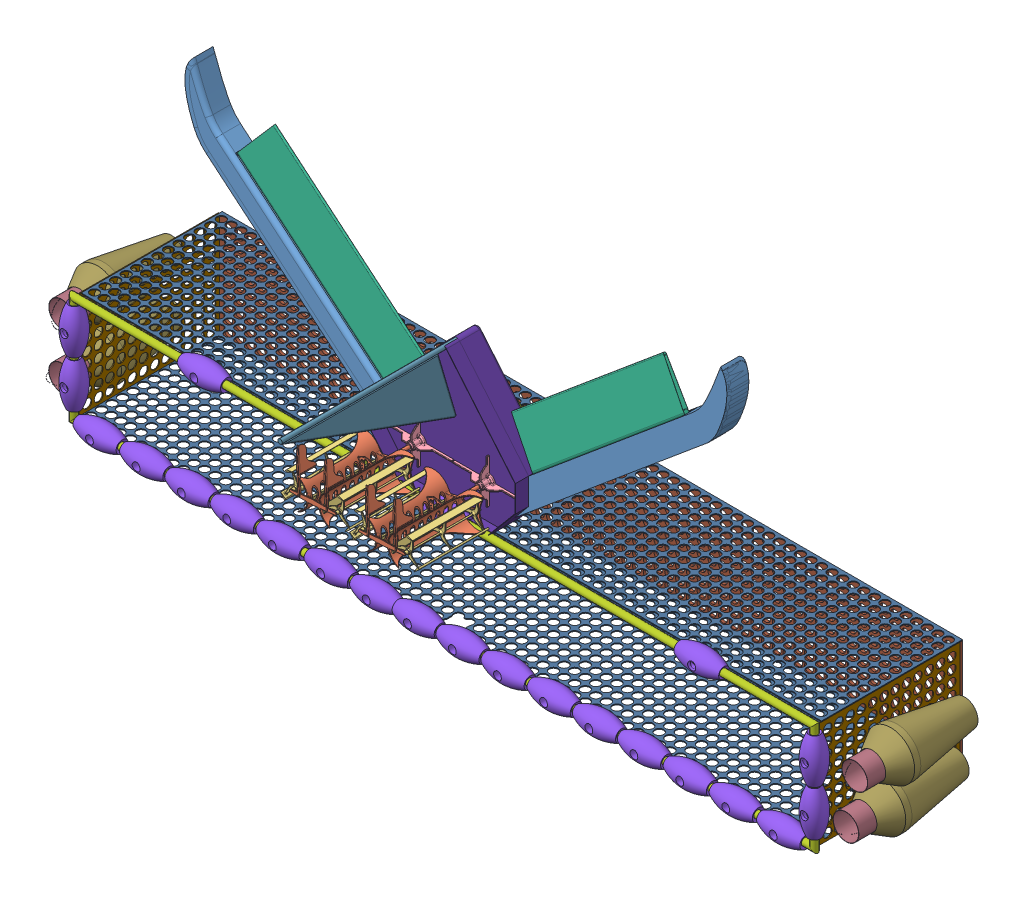
SolidWorks assembly Assembly, configuration Default. Lengths in mm.
Overall size (190923.81 84121.5 70808.31).
66 component instances, 17 part files, 22 mates.
Components (placement in the parent):
- base wings-1: base wings [Default] at (31251.053 -1037.9703 62574.9712) x (0.999998 -0.001756 0) z (0 0 1) size (49778.52 53495.45 5546.51)
- base wings-2: base wings [Default] at (4651.316 -721.6825 67574.9712) x (-1 0 0) z (0 0 -1) size (49778.52 53495.45 5546.51)
- windmill-1: windmill [Default] at (9418.4894 4145.6521 82842.4559) x (1 0 0) z (0 -1 0) size (16993.24 24410.07 14929.01)
  - venturi support-1: venturi support [Default] at (364.8029 -931.6093 16.0928) x (-0.998716 0 0.050657) z (-0.050657 0 -0.998716) size (13696.69 24410.07 13675.93)
  - blade-1: blade [Default] at (5480.8434 -190.3951 112.8514) x (0.973152 0 0.230162) z (-0.230162 0 0.973152) size (6518.55 17239.41 5772.54)
  - blade-2: blade [Default] at (-4279.5143 -190.3951 1025.3329) x (-0.23463 0 0.972085) z (-0.972085 0 -0.23463) size (6518.55 17239.41 5772.54)
  - base-1: base [Default] at (398.6318 -14556.5072 681.974) size (15500.64 2480 10000)
- windmill-2: windmill [Default] at (25075.7404 4096.6337 82842.4559) x (0.999998 -0.001756 0) z (-0.001756 -0.999998 0) size (16993.24 24410.07 14929.01)
  - venturi support-1: venturi support [Default] at (364.8029 -931.6093 16.0928) x (-0.998716 0 0.050657) z (-0.050657 0 -0.998716) size (13696.69 24410.07 13675.93)
  - blade-1: blade [Default] at (5480.8434 -190.3951 112.8514) x (0.973152 0 0.230162) z (-0.230162 0 0.973152) size (6518.55 17239.41 5772.54)
  - blade-2: blade [Default] at (-4279.5143 -190.3951 1025.3329) x (-0.23463 0 0.972085) z (-0.972085 0 -0.23463) size (6518.55 17239.41 5772.54)
  - base-1: base [Default] at (398.6318 -14556.5072 681.974) size (15500.64 2480 10000)
- conveyor belt 2-1: conveyor belt 2 [Default] at (33342.9386 1115.1594 63322.2672) x (0.767172 0.641441 0) z (-0.641441 0.767172 0) size (50500 500 3500)
- conveyor belt 1-2: conveyor belt 1 [Default] at (44175.8822 32269.4925 64379.4351) x (-0.634283 0.758611 -0.148981) z (0.767172 0.641441 0) size (10796.48 1040.31 45000)
- conveyor belt 1-3: conveyor belt 1 [Default] at (-8893.9154 31799.3186 63379.2858) x (0.635614 0.757495 -0.148981) z (-0.766044 0.642788 0) size (10796.48 1040.31 45000)
- container-1: container [Default] at (578.0262 -38708.3578 38147.6503) x (1 -0.000878 0) z (0 0 1) size (190898.47 28939.25 35884.66)
  - frame-1: frame [Default] at (17361.6165 21708.8418 32016.9805) size (169596.12 25611.45 1626.79)
  - floater-1: floater [Default] at (-36980.1605 33708.8405 31993.2415) x (0 -1 0) z (0 0 -1) size (4939.25 10116.9 5478.32)
  - floater-2: floater [Default] at (17513.3172 33708.8405 31993.2415) x (0 -1 0) z (0 0 -1) size (4939.25 10116.9 5478.32)
  - floater-3: floater [Default] at (-66640.5125 16945.0389 31993.2415) x (-1 0 0) z (0 0 -1) size (4939.25 10116.9 5478.32)
  - floater-4: floater [Default] at (-66640.5125 27584.3883 31993.2415) x (-1 0 0) z (0 0 -1) size (4939.25 10116.9 5478.32)
  - floater-6: floater [Default] at (75771.6013 33713.1297 31993.2415) x (0 1 0) z (0 0 -1) size (4939.25 10116.9 5478.32)
  - floater-7: floater [Default] at (101359.4875 27327.3859 31993.2415) x (-1 0 0) z (0 0 -1) size (4939.25 10116.9 5478.32)
  - floater-8: floater [Default] at (-60631.704 9708.8405 31993.2415) x (0 -1 0) z (0 0 -1) size (4939.25 10116.9 5478.32)
  - floater-9: floater [Default] at (11553.9346 9708.8405 31993.2415) x (0 -1 0) z (0 0 -1) size (4939.25 10116.9 5478.32)
  - floater-10: floater [Default] at (-39783.264 9708.8405 31993.2415) x (0 -1 0) z (0 0 -1) size (4939.25 10116.9 5478.32)
  - floater-11: floater [Default] at (-19127.0581 9708.8405 31993.2415) x (0 -1 0) z (0 0 -1) size (4939.25 10116.9 5478.32)
  - floater-12: floater [Default] at (-50051.5647 9708.8405 31993.2415) x (0 -1 0) z (0 0 -1) size (4939.25 10116.9 5478.32)
  - floater-13: floater [Default] at (-29484.4017 9708.8405 31993.2415) x (0 -1 0) z (0 0 -1) size (4939.25 10116.9 5478.32)
  - floater-14: floater [Default] at (-8179.3773 9708.8405 31993.2415) x (0 -1 0) z (0 0 -1) size (4939.25 10116.9 5478.32)
  - floater-15: floater [Default] at (101359.4875 16980.1616 31993.2415) x (-1 0 0) z (0 0 -1) size (4939.25 10116.9 5478.32)
  - floater-17: floater [Default] at (21716.578 9708.8405 31993.2415) x (0 -1 0) z (0 0 -1) size (4939.25 10116.9 5478.32)
  - floater-18: floater [Default] at (42423.5451 9708.8405 31993.2415) x (0 -1 0) z (0 0 -1) size (4939.25 10116.9 5478.32)
  - floater-19: floater [Default] at (73317.7347 9708.8405 31993.2415) x (0 -1 0) z (0 0 -1) size (4939.25 10116.9 5478.32)
  - floater-20: floater [Default] at (62930.1515 9708.8405 31993.2415) x (0 -1 0) z (0 0 -1) size (4939.25 10116.9 5478.32)
  - floater-21: floater [Default] at (31967.2879 9708.8405 31993.2415) x (0 -1 0) z (0 0 -1) size (4939.25 10116.9 5478.32)
  - floater-22: floater [Default] at (52705.8058 9708.8405 31993.2415) x (0 -1 0) z (0 0 -1) size (4939.25 10116.9 5478.32)
  - floater-23: floater [Default] at (2170.3595 9708.8405 31993.2415) x (0 -1 0) z (0 0 -1) size (4939.25 10116.9 5478.32)
  - floater-24: floater [Default] at (83761.0281 9708.8405 31993.2415) x (0 -1 0) z (0 0 -1) size (4939.25 10116.9 5478.32)
  - floater-25: floater [Default] at (94524.1889 9708.8405 31993.2415) x (0 -1 0) z (0 0 -1) size (4939.25 10116.9 5478.32)
  - net 2-1: net 2 [Default] at (-65874.4507 20880.3654 11266.4991) size (200 24000 32000)
  - net-1: net [Default] at (-3309.8575 10472.5139 15045.9364) x (0 1 0) z (1 0 0) size (200 32000 168000)
  - net 2-2: net 2 [Default] at (102123.161 20680.3654 11266.4991) size (200 24000 32000)
  - net 3-1: net 3 [Default] at (17739.3734 21765.6747 -1155.9867) size (168000 24000 600)
  - net-2: net [Default] at (-3112.2459 34472.5139 14445.9364) x (0 1 0) z (1 0 0) size (200 32000 168000)
  - Assem1 seabin-2: Assem1 seabin [Default] at (106123.161 14906.2847 17601.7317) x (0 -1 0) z (-1 0 0) size (10900.86 27239.5 10900.86)
    - sea bin 1-1: sea bin 1 [Default] at origin size (10900.86 20941.88 10900.86)
    - filter candle-1: filter candle [Default] at (0.0002 479.1714 -0.0002) x (0.994441 0 -0.105296) z (0 -1 0) size (5880 5880 23323.37)
  - Assem1 seabin-3: Assem1 seabin [Default] at (108123.161 25912.9475 17601.7317) x (1 0 0) z (0 -1 0) size (10900.86 27239.5 10900.86)
    - sea bin 1-1: sea bin 1 [Default] at origin size (10900.86 20941.88 10900.86)
    - filter candle-1: filter candle [Default] at (0.0002 479.1714 -0.0002) x (0.994441 0 -0.105296) z (0 -1 0) size (5880 5880 23323.37)
  - Assem1 seabin-4: Assem1 seabin [Default] at (-71874.4507 26498.5801 17601.7317) x (1 0 0) z (0 -1 0) size (10900.86 27239.5 10900.86)
    - sea bin 1-1: sea bin 1 [Default] at origin size (10900.86 20941.88 10900.86)
    - filter candle-1: filter candle [Default] at (0.0002 479.1714 -0.0002) x (0.994441 0 -0.105296) z (0 -1 0) size (5880 5880 23323.37)
  - Assem1 seabin-5: Assem1 seabin [Default] at (-71874.4507 13969.2976 17601.7317) x (0 -1 0) z (-1 0 0) size (10900.86 27239.5 10900.86)
    - sea bin 1-1: sea bin 1 [Default] at origin size (10900.86 20941.88 10900.86)
    - filter candle-1: filter candle [Default] at (0.0002 479.1714 -0.0002) x (0.994441 0 -0.105296) z (0 -1 0) size (5880 5880 23323.37)
- sail-1: sail [Default] at (18098.9288 27411.8835 107574.9712) x (-0.000878 -1 0) z (0 0 -1) size (15265.92 1000 40000)
- Jet Engine Turbine Final Assembly-1: Jet Engine Turbine Final Assembly [Default] at (24466.2361 10219.7756 56980.9408) size (11877.76 12076.56 4000)
  - Propeller Hub-1: Propeller Hub [Default] at (195.4203 1441.516 5014.3153) size (2939.06 2957.93 4000)
  - Jet Engine Fan-1: Jet Engine Fan [Default] at (195.421 1441.516 5014.3153) x (-0.961422 0.275079 0) z (0 0 1) size (9766.73 9766.73 1558.36)
- Jet Engine Turbine Final Assembly-2: Jet Engine Turbine Final Assembly [Default] at (11337.2872 10339.4804 56980.9408) size (11877.76 12076.56 4000)
  - Propeller Hub-1: Propeller Hub [Default] at (195.4203 1441.516 5014.3153) size (2939.06 2957.93 4000)
  - Jet Engine Fan-1: Jet Engine Fan [Default] at (195.421 1441.516 5014.3153) x (-0.961422 0.275079 0) z (0 0 1) size (9766.73 9766.73 1558.36)
- base model-2: base model [Default] at (18077.9009 3468.6636 65074.9712) x (-1 0.000878 0) z (0 0 -1) size (32855.75 32682.7 8000)
- conveyor belt 2-3: conveyor belt 2 [Default] at (-35914.5814 33656.5529 62922.2672) x (0.766044 -0.642788 0) z (0.642788 0.766044 0) size (50500 500 3500)
Mates (geometry in assembly coordinates):
- Distance6: distance = 500 mm anti-aligned: plane of base wings-1 through (68203.2625 42893.0539 62584.9712) normal (0 0 1); plane of conveyor belt 2-1 through (65555.6667 -37475.9994 63084.9712) normal (0 0 -1)
- Distance5: distance = 300 mm anti-aligned: plane of base wings-1 through (31244.6385 -1030.2985 67574.9712) normal (-0.641441 0.767172 0); plane of conveyor belt 2-1 through (71590.0529 33093.986 63322.2672) normal (0.641441 -0.767172 0)
- Width1: width aligned: plane of base model-2 through (34505.2253 2833.2915 70574.9712) normal (1 -0.000878 0); plane of base model-2 through (1654.7552 8862.1445 70574.9712) normal (-1 0.000878 0); plane of container-1/net 2-2 through (102148.1478 -29086.5719 69366.6636) normal (1 -0.000878 0); plane of container-1/net 2-1 through (-66028.1455 -4738.8633 69366.6636) normal (-1 0.000878 0)
- Coincident48: coincident aligned: plane of container-1/net-2 through (19771.6767 -6814.217 64456.2529) normal (0 0 1); plane of base model-2 through (16082.924 9189.0288 64456.2529) normal (0 0 1)
- Coincident49: coincident anti-aligned: plane of container-1/net-2 through (102169.4012 -4886.5813 36766.6636) normal (0.000878 1 0); plane of base model-2 through (8070.6317 -4803.9399 62824.9712) normal (-0.000878 -1 0)
- Coincident50: coincident anti-aligned: plane of sail-1 through (18098.9288 27411.8835 67574.9712) normal (0 0 -1); plane of base model-2 through (18077.9009 3468.6636 67574.9712) normal (0 0 1)
- Coincident51: coincident aligned: plane of sail-1; plane of base model-2
- Coincident56: coincident anti-aligned: plane of Jet Engine Turbine Final Assembly-1/Propeller Hub-1 through (24661.6572 12730.7268 62574.9712) normal (0 0 1); plane of base model-2 through (18077.9009 3468.6636 62574.9712) normal (0 0 -1)
- Coincident57: coincident anti-aligned: plane of Jet Engine Turbine Final Assembly-2/Propeller Hub-1 through (11532.7082 12850.4316 62574.9712) normal (0 0 1); plane of base model-2 through (18077.9009 3468.6636 62574.9712) normal (0 0 -1)
- Coincident62: coincident anti-aligned: plane of windmill-1/base-1 through (9817.1305 3463.678 67574.9712) normal (0 0 -1); plane of base model-2 through (18077.9009 3468.6636 67574.9712) normal (0 0 1)
- Coincident63: coincident anti-aligned: plane of windmill-2/base-1 through (25473.1831 3413.9604 67574.9712) normal (0 0 -1); plane of base model-2 through (18077.9009 3468.6636 67574.9712) normal (0 0 1)
- Coincident64: coincident anti-aligned: plane of base wings-1 through (34468.3536 2789.4279 67574.9712) normal (-0.76548 0.64346 0); plane of base model-2 through (28070.624 -4821.5047 62824.9712) normal (0.76548 -0.64346 0)
- Coincident65: coincident anti-aligned: plane of base wings-2 through (1440.7431 3111.3608 62574.9712) normal (0.766609 0.642115 0); plane of base model-2 through (1649.4858 2862.1468 62824.9712) normal (-0.766609 -0.642115 0)
- Coincident66: coincident aligned: plane of base wings-1 through (68203.2625 42893.0539 67574.9712) normal (0 0 1); plane of base model-2 through (18077.9009 3468.6636 67574.9712) normal (0 0 1)
- Coincident67: coincident aligned: plane of base wings-2 through (-32223.6726 43274.1797 67574.9712) normal (0 0 1); plane of base model-2 through (18077.9009 3468.6636 67574.9712) normal (0 0 1)
- Coincident71: coincident: point of base wings-1; moEndPointRef_w of base model-2
- Coincident80: coincident anti-aligned: plane of base wings-1 through (65504.5129 41837.4255 63574.9712) normal (-0.767172 -0.641441 0); plane of conveyor belt 1-2 through (68834.6194 37854.5726 66116.9404) normal (0.767172 0.641441 0)
- Angle4: planar angle = 0.174533 rad aligned: plane of conveyor belt 1-2 through (25940.7306 2092.1521 66631.0565) normal (-0.111385 0.133218 0.984808); plane of base wings-1 through (68203.2625 42893.0539 62584.9712) normal (0 0 1)
- Angle5: planar angle = 0.174533 rad: plane of conveyor belt 1-3 through (15620.4023 9136.4173 63893.8829) normal (0.111619 0.133022 0.984808); plane of base wings-2 through (-32223.6726 43274.1797 62584.9712) normal (0 0 1)
- Distance9: distance = 100 mm anti-aligned: plane of conveyor belt 2-3 through (-68258.2301 -4824.9462 62684.9712) normal (0 0 -1); plane of base wings-2 through (-32223.6726 43274.1797 62584.9712) normal (0 0 1)
- Coincident90: coincident anti-aligned: plane of base wings-2 through (4657.7439 -714.0221 62574.9712) normal (0.642788 0.766044 0); plane of conveyor belt 2-3 through (-36186.6153 33558.4647 62922.2672) normal (-0.642788 -0.766044 0)
- Coincident92: coincident anti-aligned: plane of base wings-2 through (-29526.7813 42213.8126 66574.9712) normal (0.766044 -0.642788 0); plane of conveyor belt 1-3 through (-33542.8044 37427.7026 65116.7911) normal (-0.766044 0.642788 0)
